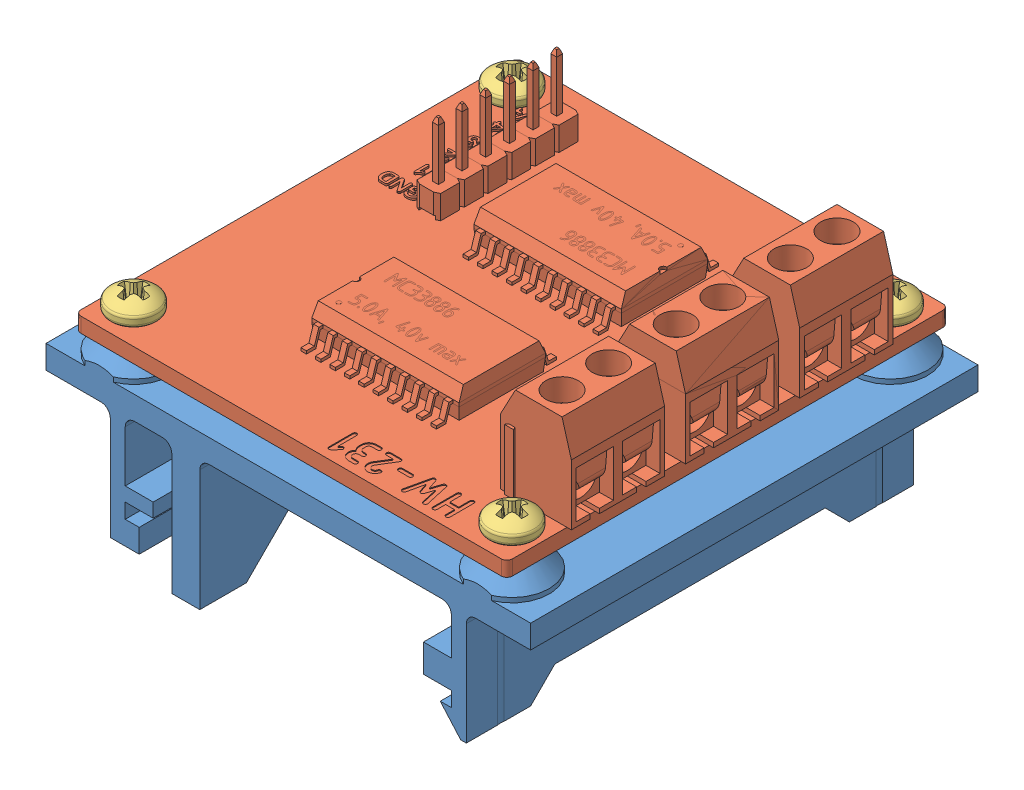
SolidWorks assembly MD_assem, configuration Default. Lengths in mm.
Overall size (52 30.6 48).
7 component instances, 4 part files, 21 mates.
Components (placement in the parent):
- motorDriverBracket_v2-1: motorDriverBracket_v2 [Default] at origin size (52 19 48)
- motorDriver-1: motorDriver [Default] at (0 13 0) x (0 0 1) z (0 1 0) size (47.4 46.77 14.5)
- screw M2.5-1: screw M2.5 [6mm] at (20.3 8.6 20.3) x (1 0 0) z (0 1 0) size (5 5 8.1)
- screw M2.5-2: screw M2.5 [6mm] at (20.3 8.6 -20.3) x (1 0 0) z (0 1 0) size (5 5 8.1)
- screw M2.5-4: screw M2.5 [6mm] at (-20.3 8.6 -20.3) x (1 0 0) z (0 1 0) size (5 5 8.1)
- screw M2.5-5: screw M2.5 [6mm] at (-20.3 8.6 20.3) x (1 0 0) z (0 1 0) size (5 5 8.1)
- insertM2.5x3.4-1: insertM2.5x3.4 [4mm] at (20.3 13 20.3) size (4.37 3.69 4.37)
Mates (geometry in assembly coordinates):
- Coincident1: coincident aligned: plane of mDrvBrktV2-1 through (0 0 0) normal (0 1 0)
- Coincident2: coincident aligned: plane of mDrvBrktV2-1 through (0 0 0) normal (1 0 0)
- Coincident3: coincident aligned: plane of mDrvBrktV2-1 through (0 0 0) normal (0 0 1)
- Concentric1: concentric anti-aligned: cylinder of mDrvBrktV2-1 through (20.3 -6 20.3) axis (0 1 0) radius 1.25; line of mtrDrvPRT-1 through (20.3 14.6 20.3) axis (0 -1 0)
- Coincident4: coincident anti-aligned: plane of mDrvBrktV2-1 through (20.3 13 20.3) normal (0 1 0); plane of mtrDrvPRT-1 through (0 13 0) normal (0 -1 0)
- Coincident5: coincident aligned: plane of mtrDrvPRT-1 through (0 13 0) normal (0 0 1)
- Coincident6: coincident anti-aligned: line of screw M2.5-1 through (20.3 20.201 20.3) axis (0 -1 0)
- Coincident7: coincident aligned: plane of mtrDrvPRT-1 through (0 14.6 0) normal (0 1 0); plane of screw M2.5x6-1 through (20.3 14.6 20.3) normal (0 1 0)
- Parallel1: parallel aligned: plane of screw M2.5x6-1 through (20.3 8.6 20.3) normal (1 0 0)
- Coincident8: coincident aligned: line of mtrDrvPRT-1 through (20.3 14.6 -20.3) axis (0 -1 0); line of screw M2.5x6-2 through (20.3 20.201 -20.3) axis (0 -1 0)
- Coincident9: coincident aligned: plane of mtrDrvPRT-1 through (0 14.6 0) normal (0 1 0); plane of screw M2.5x6-2 through (20.3 14.6 -20.3) normal (0 1 0)
- Parallel2: parallel aligned: plane of screw M2.5x6-2 through (20.3 8.6 -20.3) normal (1 0 0)
- Coincident11: coincident aligned: line of mtrDrvPRT-1 through (-20.3 14.6 -20.3) axis (0 -1 0); line of screw M2.5x6-4 through (-20.3 20.201 -20.3) axis (0 -1 0)
- Coincident12: coincident aligned: plane of mtrDrvPRT-1 through (0 14.6 0) normal (0 1 0); plane of screw M2.5x6-4 through (-20.3 14.6 -20.3) normal (0 1 0)
- Parallel4: parallel aligned: plane of screw M2.5x6-4 through (-20.3 8.6 -20.3) normal (1 0 0)
- Coincident13: coincident aligned: plane of mtrDrvPRT-1 through (0 14.6 0) normal (0 1 0); plane of screw M2.5x6-5 through (-20.3 14.6 20.3) normal (0 1 0)
- Parallel5: parallel aligned: plane of screw M2.5x6-5 through (-20.3 8.6 20.3) normal (1 0 0)
- Coincident14: coincident aligned: line of mtrDrvPRT-1 through (-20.3 14.6 20.3) axis (0 -1 0); line of screw M2.5x6-5 through (-20.3 20.201 20.3) axis (0 -1 0)
- Coincident16: coincident aligned: line of insertM2.5x3.4-1 through (20.3 8.1207 20.3) axis (0 1 0)
- Coincident17: coincident aligned: plane of insertM2.5x3.4-1 through (20.3 13 20.3) normal (0 1 0)
- Parallel7: parallel aligned: plane of insertM2.5x3.4-1 through (20.3 13 20.3) normal (1 0 0)
